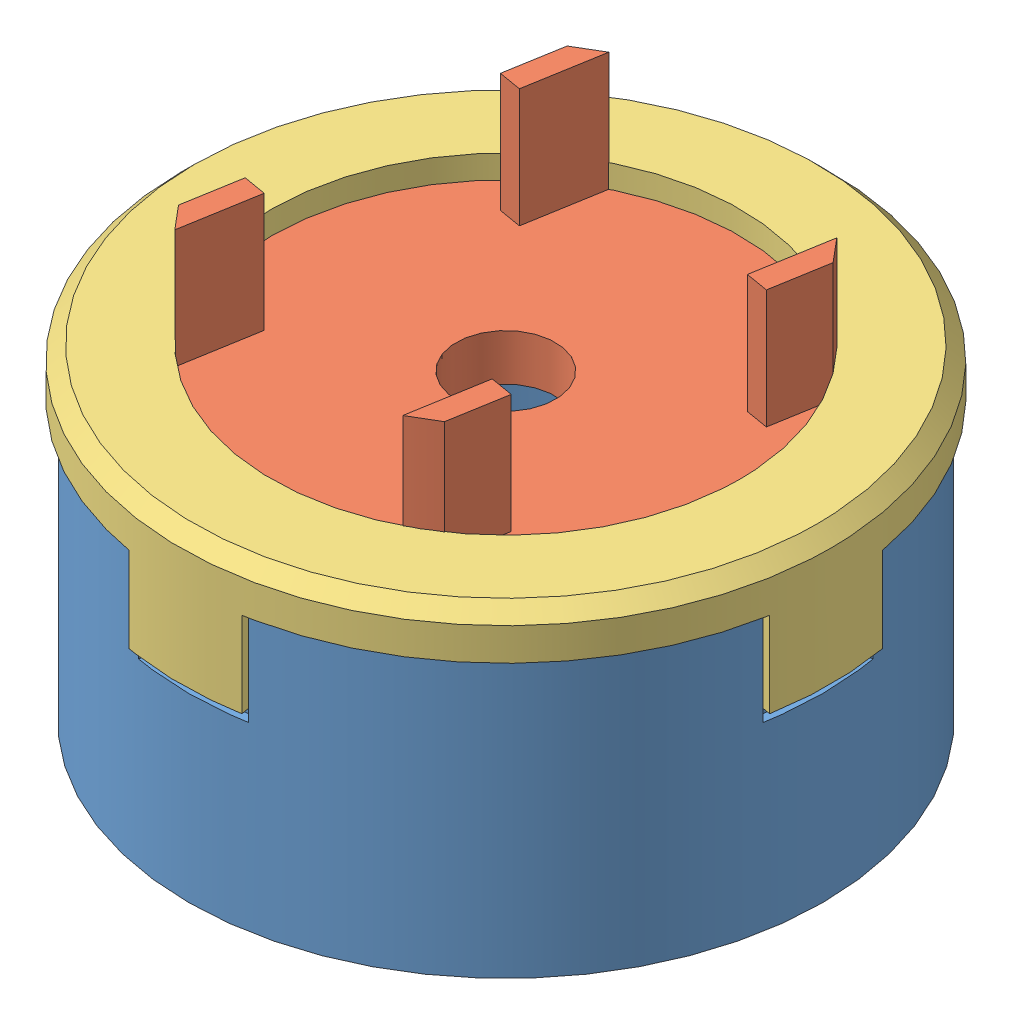
SolidWorks assembly test1, configuration Default. Lengths in mm.
Overall size (141.99 90.56 141.99).
3 component instances, 3 part files, 6 mates.
Components (placement in the parent):
- Część1^test1-1: Część1^test1 [Domyślna] at origin size (136.49 60 136.49) (virtual)
- Część2^test1-1: Część2^test1 [Domyślna] at (0 60 0) x (-0.16786 0 0.985811) z (-0.985811 0 -0.16786) size (123.08 35.56 123.08) (virtual)
- Część3^test1-1: Część3^test1 [Domyślna] at (0 60 0) x (0 0 -1) z (1 0 0) size (140.04 28.35 140.04) (virtual)
Mates (geometry in assembly coordinates):
- Wspólnie1: coordinate: point of Część1^test1-1; point of assembly
- Wspólnie2: coincident aligned: plane of Część1^test1-1 through (0 60 0) normal (0 1 0); plane of Część2^test1-1 through (0 60 0) normal (0 1 0)
- Koncentryczne1: concentric aligned: cylinder of Część1^test1-1 through (0 60 0) axis (0 -1 0) radius 68.2443; cylinder of Część2^test1-1 through (0 65 0) axis (0 -1 0) radius 61.5381
- Wspólnie6: coincident aligned: plane of Część1^test1-1 through (0 60 0) normal (0 1 0); plane of Część3^test1-1 through (0 60 0) normal (0 1 0)
- Koncentryczne2: concentric aligned: cylinder of Część1^test1-1 through (0 60 0) axis (0 -1 0) radius 68.2443; cylinder of Część3^test1-1 through (0 65 0) axis (0 -1 0) radius 70.0223
- Wspólnie7: coincident anti-aligned: plane of Część1^test1-1 through (0 0 0) normal (-0.173648 0 -0.984808); plane of Część3^test1-1 through (0 60 0) normal (0.173648 0 0.984808)
